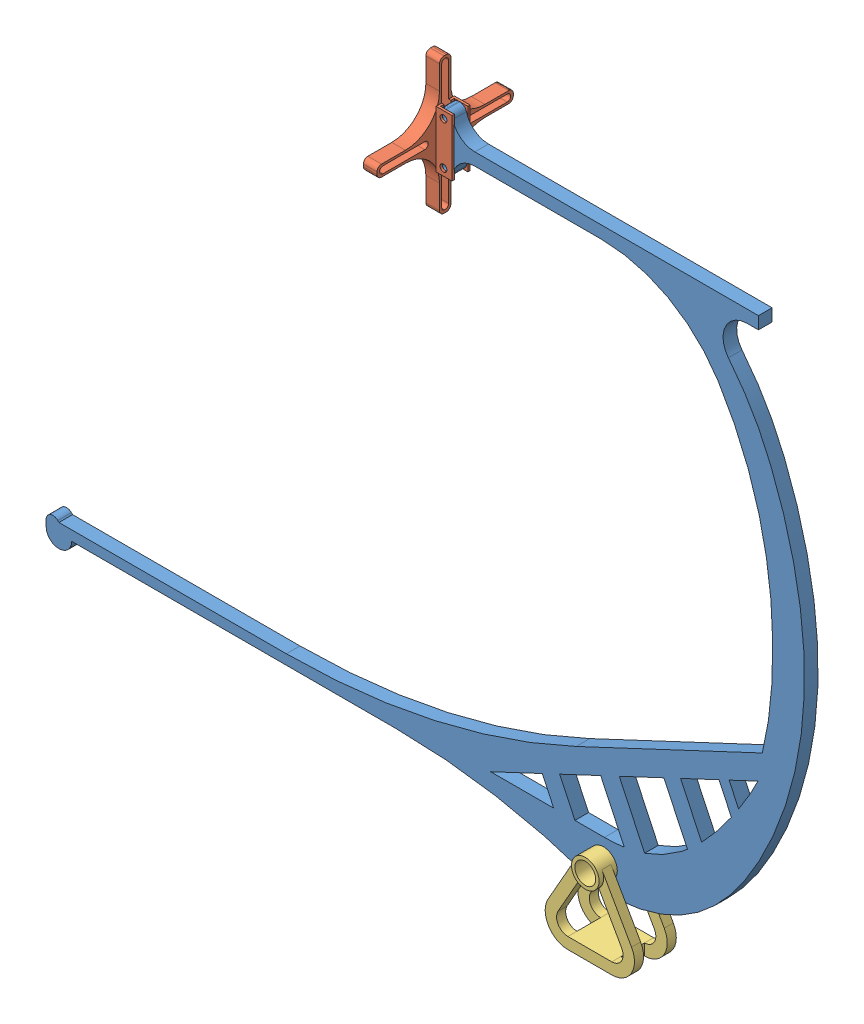
SolidWorks assembly Assem1, configuration Default. Lengths in mm.
Overall size (340.22 304.64 60).
3 component instances, 3 part files, 0 mates.
Components (placement in the parent):
- Main frame-1: Main frame [Default] at (203.0747 73.6428 291.5867) size (340.22 263.37 6)
- Motor Mount-1: Motor Mount [Default] at (133.9921 301.1627 291.5524) size (13 60 60)
- Stand and Pivot-1: Stand and Pivot [Default] at (202.8522 73.9428 291.7575) size (39.31 41.02 22.4)
